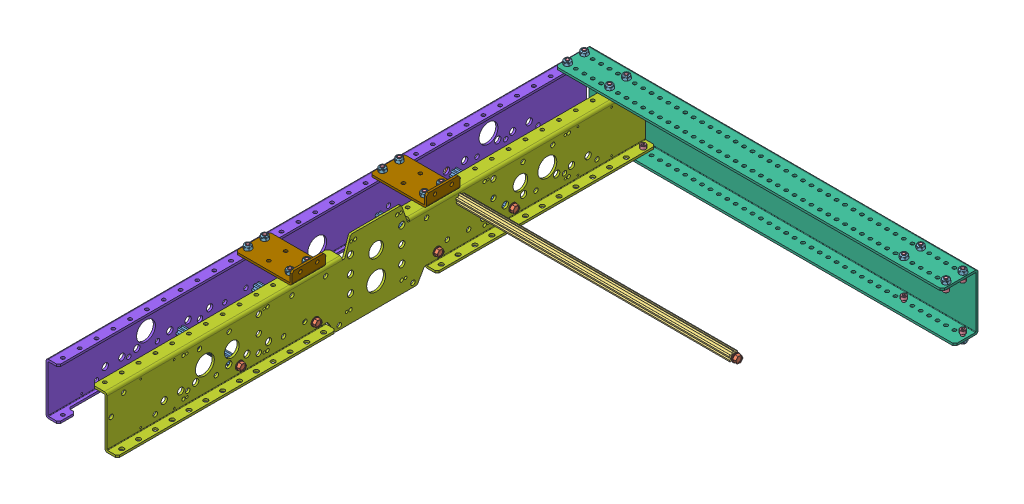
SolidWorks assembly AM14U3Long_Frame_Half, configuration Default. Lengths in mm.
Overall size (596.14 116.33 816.74).
60 component instances, 9 part files, 0 mates.
Components (placement in the parent):
- 500Churro_3.375-1: 500Churro_3.375 [Default] at (-501.65 -66.929 448.437) x (0 0 1) z (-1 0 0) size (14.66 12.7 85.72)
- 500Churro_3.375-2: 500Churro_3.375 [Default] at (-501.65 -66.929 562.737) x (0 0 1) z (-1 0 0) size (14.66 12.7 85.72)
- 500Churro_3.375-3: 500Churro_3.375 [Default] at (-501.65 -66.929 264.287) x (0 0 1) z (-1 0 0) size (14.66 12.7 85.72)
- 500Churro_3.375-4: 500Churro_3.375 [Default] at (-501.65 -66.929 149.987) x (0 0 1) z (-1 0 0) size (14.66 12.7 85.72)
- ThreadRollingScrew_0.25-20x0.75_FHTS 0.25-20-G-0.75-C-1: ThreadRollingScrew_0.25-20x0.75_FHTS 0.25-20-G-0.75-C [Default] at (-498.475 -66.929 562.737) x (-1 0 0) z (0 0.924225 0.381849) size (24.64 12.19 12.19)
- ThreadRollingScrew_0.25-20x0.75_FHTS 0.25-20-G-0.75-C-2: ThreadRollingScrew_0.25-20x0.75_FHTS 0.25-20-G-0.75-C [Default] at (-498.475 -66.929 448.437) x (-1 0 0) z (0 0.924225 0.381849) size (24.64 12.19 12.19)
- ThreadRollingScrew_0.25-20x0.75_FHTS 0.25-20-G-0.75-C-3: ThreadRollingScrew_0.25-20x0.75_FHTS 0.25-20-G-0.75-C [Default] at (-498.475 -66.929 264.287) x (-1 0 0) z (0 0.924225 0.381849) size (24.64 12.19 12.19)
- ThreadRollingScrew_0.25-20x0.75_FHTS 0.25-20-G-0.75-C-4: ThreadRollingScrew_0.25-20x0.75_FHTS 0.25-20-G-0.75-C [Default] at (-498.475 -66.929 149.987) x (-1 0 0) z (0 0.924225 0.381849) size (24.64 12.19 12.19)
- ThreadRollingScrew_0.25-20x0.75_FHTS 0.25-20-G-0.75-C-5: ThreadRollingScrew_0.25-20x0.75_FHTS 0.25-20-G-0.75-C [Default] at (-590.55 -66.929 562.737) size (24.64 12.19 12.19)
- ThreadRollingScrew_0.25-20x0.75_FHTS 0.25-20-G-0.75-C-6: ThreadRollingScrew_0.25-20x0.75_FHTS 0.25-20-G-0.75-C [Default] at (-590.55 -66.929 448.437) size (24.64 12.19 12.19)
- ThreadRollingScrew_0.25-20x0.75_FHTS 0.25-20-G-0.75-C-7: ThreadRollingScrew_0.25-20x0.75_FHTS 0.25-20-G-0.75-C [Default] at (-590.55 -66.929 149.987) size (24.64 12.19 12.19)
- ThreadRollingScrew_0.25-20x0.75_FHTS 0.25-20-G-0.75-C-8: ThreadRollingScrew_0.25-20x0.75_FHTS 0.25-20-G-0.75-C [Default] at (-590.55 -66.929 264.287) size (24.64 12.19 12.19)
- ThreadRollingScrew_0.25-20x0.75_FHTS 0.25-20-G-0.75-C-9: ThreadRollingScrew_0.25-20x0.75_FHTS 0.25-20-G-0.75-C [Default] at (-501.65 -15.494 229.362) size (24.64 12.19 12.19)
- ThreadRollingScrew_0.25-20x0.75_FHTS 0.25-20-G-0.75-C-10: ThreadRollingScrew_0.25-20x0.75_FHTS 0.25-20-G-0.75-C [Default] at (-82.55 -15.494 229.362) x (-1 0 0) z (0 -0.924225 -0.381849) size (24.64 12.19 12.19)
- 500Churro_cut_16.25-1: 500Churro_cut_16.25 [Default] at (-85.725 -15.494 229.362) x (0 0.99241 0.122972) z (-1 0 0) size (14.66 12.7 412.75)
- Screw_SHCS_10-32x0.5_HX-SHCS 0.19-32x1.375x1-C-1: Screw_SHCS_10-32x0.5_HX-SHCS 0.19-32x1.375x1-C [Default] at (-577.85 -11.43 -11.938) x (0 1 0) z (0 0 1) size (17.53 7.94 7.94)
- Screw_SHCS_10-32x0.5_HX-SHCS 0.19-32x1.375x1-C-2: Screw_SHCS_10-32x0.5_HX-SHCS 0.19-32x1.375x1-C [Default] at (-577.85 -11.43 -37.338) x (0 1 0) z (0 0 1) size (17.53 7.94 7.94)
- Screw_SHCS_10-32x0.5_HX-SHCS 0.19-32x1.375x1-C-3: Screw_SHCS_10-32x0.5_HX-SHCS 0.19-32x1.375x1-C [Default] at (-514.35 -11.43 -37.338) x (0 1 0) z (0 0 1) size (17.53 7.94 7.94)
- Screw_SHCS_10-32x0.5_HX-SHCS 0.19-32x1.375x1-C-4: Screw_SHCS_10-32x0.5_HX-SHCS 0.19-32x1.375x1-C [Default] at (-514.35 -11.43 -11.938) x (0 1 0) z (0 0 1) size (17.53 7.94 7.94)
- Screw_SHCS_10-32x0.5_HX-SHCS 0.19-32x1.375x1-C-5: Screw_SHCS_10-32x0.5_HX-SHCS 0.19-32x1.375x1-C [Default] at (-488.95 -73.152 -37.338) x (0 -1 0) z (0 0 1) size (17.53 7.94 7.94)
- Screw_SHCS_10-32x0.5_HX-SHCS 0.19-32x1.375x1-C-6: Screw_SHCS_10-32x0.5_HX-SHCS 0.19-32x1.375x1-C [Default] at (-577.85 -73.152 -37.338) x (0 -1 0) z (0 0 1) size (17.53 7.94 7.94)
- Screw_SHCS_10-32x0.5_HX-SHCS 0.19-32x1.375x1-C-7: Screw_SHCS_10-32x0.5_HX-SHCS 0.19-32x1.375x1-C [Default] at (-6.35 -11.176 -11.938) x (0 1 0) z (-0.991845 0 0.127447) size (17.53 7.94 7.94)
- Screw_SHCS_10-32x0.5_HX-SHCS 0.19-32x1.375x1-C-8: Screw_SHCS_10-32x0.5_HX-SHCS 0.19-32x1.375x1-C [Default] at (-6.35 -11.176 -37.338) x (0 1 0) z (0.595464 0 0.803382) size (17.53 7.94 7.94)
- Screw_SHCS_10-32x0.5_HX-SHCS 0.19-32x1.375x1-C-9: Screw_SHCS_10-32x0.5_HX-SHCS 0.19-32x1.375x1-C [Default] at (-69.85 -11.176 -11.938) x (0 1 0) z (0.578861 0 0.815426) size (17.53 7.94 7.94)
- Screw_SHCS_10-32x0.5_HX-SHCS 0.19-32x1.375x1-C-10: Screw_SHCS_10-32x0.5_HX-SHCS 0.19-32x1.375x1-C [Default] at (-69.85 -11.176 -37.338) x (0 1 0) z (0.958905 0 0.283727) size (17.53 7.94 7.94)
- Screw_SHCS_10-32x0.5_HX-SHCS 0.19-32x1.375x1-C-11: Screw_SHCS_10-32x0.5_HX-SHCS 0.19-32x1.375x1-C [Default] at (-6.35 -73.406 -37.338) x (0 -1 0) z (-0.989362 0 -0.145473) size (17.53 7.94 7.94)
- Screw_SHCS_10-32x0.5_HX-SHCS 0.19-32x1.375x1-C-12: Screw_SHCS_10-32x0.5_HX-SHCS 0.19-32x1.375x1-C [Default] at (-95.25 -73.406 -37.338) x (0 -1 0) z (-0.875347 0 0.483496) size (17.53 7.94 7.94)
- NylockNut_10-32-1: NylockNut_10-32 [Default] at (-69.85 0 -11.938) x (1 0 0) z (0 1 0) size (9.53 11 5.96)
- NylockNut_10-32-2: NylockNut_10-32 [Default] at (-69.85 0 -37.338) x (1 0 0) z (0 1 0) size (9.53 11 5.96)
- NylockNut_10-32-3: NylockNut_10-32 [Default] at (-6.35 0 -37.338) x (1 0 0) z (0 1 0) size (9.53 11 5.96)
- NylockNut_10-32-4: NylockNut_10-32 [Default] at (-6.35 0 -11.938) x (1 0 0) z (0 1 0) size (9.53 11 5.96)
- NylockNut_10-32-5: NylockNut_10-32 [Default] at (-6.35 -84.582 -37.338) x (1 0 0) z (0 -1 0) size (9.53 11 5.96)
- NylockNut_10-32-6: NylockNut_10-32 [Default] at (-95.25 -84.582 -37.338) x (1 0 0) z (0 -1 0) size (9.53 11 5.96)
- NylockNut_10-32-7: NylockNut_10-32 [Default] at (-514.35 0 -11.938) x (1 0 0) z (0 1 0) size (9.53 11 5.96)
- NylockNut_10-32-8: NylockNut_10-32 [Default] at (-514.35 0 -37.338) x (1 0 0) z (0 1 0) size (9.53 11 5.96)
- NylockNut_10-32-9: NylockNut_10-32 [Default] at (-577.85 0 -37.338) x (1 0 0) z (0 1 0) size (9.53 11 5.96)
- NylockNut_10-32-10: NylockNut_10-32 [Default] at (-577.85 0 -11.938) x (1 0 0) z (0 1 0) size (9.53 11 5.96)
- NylockNut_10-32-11: NylockNut_10-32 [Default] at (-488.95 -84.582 -37.338) x (1 0 0) z (0 -1 0) size (9.53 11 5.96)
- NylockNut_10-32-12: NylockNut_10-32 [Default] at (-577.85 -84.582 -37.338) x (1 0 0) z (0 -1 0) size (9.53 11 5.96)
- Screw_SHCS_10-32x0.5_HX-SHCS 0.19-32x1.375x1-C-13: Screw_SHCS_10-32x0.5_HX-SHCS 0.19-32x1.375x1-C [Default] at (-577.85 -11.43 445.262) x (0 1 0) z (0 0 1) size (17.53 7.94 7.94)
- Screw_SHCS_10-32x0.5_HX-SHCS 0.19-32x1.375x1-C-14: Screw_SHCS_10-32x0.5_HX-SHCS 0.19-32x1.375x1-C [Default] at (-577.85 -11.43 470.662) x (0 1 0) z (0 0 1) size (17.53 7.94 7.94)
- Screw_SHCS_10-32x0.5_HX-SHCS 0.19-32x1.375x1-C-15: Screw_SHCS_10-32x0.5_HX-SHCS 0.19-32x1.375x1-C [Default] at (-514.35 -11.43 445.262) x (0 1 0) z (0 0 1) size (17.53 7.94 7.94)
- Screw_SHCS_10-32x0.5_HX-SHCS 0.19-32x1.375x1-C-16: Screw_SHCS_10-32x0.5_HX-SHCS 0.19-32x1.375x1-C [Default] at (-514.35 -11.43 470.662) x (0 1 0) z (0 0 1) size (17.53 7.94 7.94)
- Screw_SHCS_10-32x0.5_HX-SHCS 0.19-32x1.375x1-C-17: Screw_SHCS_10-32x0.5_HX-SHCS 0.19-32x1.375x1-C [Default] at (-577.85 -11.43 267.462) x (0 1 0) z (0 0 1) size (17.53 7.94 7.94)
- Screw_SHCS_10-32x0.5_HX-SHCS 0.19-32x1.375x1-C-18: Screw_SHCS_10-32x0.5_HX-SHCS 0.19-32x1.375x1-C [Default] at (-577.85 -11.43 242.062) x (0 1 0) z (0 0 1) size (17.53 7.94 7.94)
- Screw_SHCS_10-32x0.5_HX-SHCS 0.19-32x1.375x1-C-19: Screw_SHCS_10-32x0.5_HX-SHCS 0.19-32x1.375x1-C [Default] at (-514.35 -11.43 242.062) x (0 1 0) z (0 0 1) size (17.53 7.94 7.94)
- Screw_SHCS_10-32x0.5_HX-SHCS 0.19-32x1.375x1-C-20: Screw_SHCS_10-32x0.5_HX-SHCS 0.19-32x1.375x1-C [Default] at (-514.35 -11.43 267.462) x (0 1 0) z (0 0 1) size (17.53 7.94 7.94)
- NylockNut_10-32-13: NylockNut_10-32 [Default] at (-514.35 -0.254 267.462) x (1 0 0) z (0 1 0) size (9.53 11 5.96)
- NylockNut_10-32-14: NylockNut_10-32 [Default] at (-514.35 -0.254 242.062) x (1 0 0) z (0 1 0) size (9.53 11 5.96)
- NylockNut_10-32-15: NylockNut_10-32 [Default] at (-577.85 -0.254 267.462) x (1 0 0) z (0 1 0) size (9.53 11 5.96)
- NylockNut_10-32-16: NylockNut_10-32 [Default] at (-577.85 -0.254 242.062) x (1 0 0) z (0 1 0) size (9.53 11 5.96)
- NylockNut_10-32-17: NylockNut_10-32 [Default] at (-514.35 -0.254 470.662) x (1 0 0) z (0 1 0) size (9.53 11 5.96)
- NylockNut_10-32-18: NylockNut_10-32 [Default] at (-577.85 -0.254 470.662) x (1 0 0) z (0 1 0) size (9.53 11 5.96)
- NylockNut_10-32-19: NylockNut_10-32 [Default] at (-577.85 -0.254 445.262) x (1 0 0) z (0 1 0) size (9.53 11 5.96)
- NylockNut_10-32-20: NylockNut_10-32 [Default] at (-514.35 -0.254 445.262) x (1 0 0) z (0 1 0) size (9.53 11 5.96)
- AM14U3EndPlate_Long-1: AM14U3EndPlate_Long [Default] at (-488.098 60.9785 -76.8664) x (1 0 0) z (0 -1 0) size (584.2 53.97 84.58)
- AM14U3InnerPlate_Long-1: AM14U3InnerPlate_Long [Default] at (-501.65 -77.216 762.762) x (0 0 -1) z (0 -1 0) size (812.8 38.1 116.33)
- AM14U3OuterPlate_Long_DefaultSM-FLAT-PATTERN-1: AM14U3OuterPlate_Long_DefaultSM-FLAT-PATTERN [Default] at (-587.375 -77.216 -50.038) x (0 0 1) z (0 -1 0) size (812.8 19.05 77.72)
- Bracket_2x3-1: Bracket_2x3 [Default] at (-584.2 -3.429 496.062) size (85.72 19.05 50.8)
- Bracket_2x3-2: Bracket_2x3 [Default] at (-584.2 -3.429 292.862) size (85.72 19.05 50.8)
